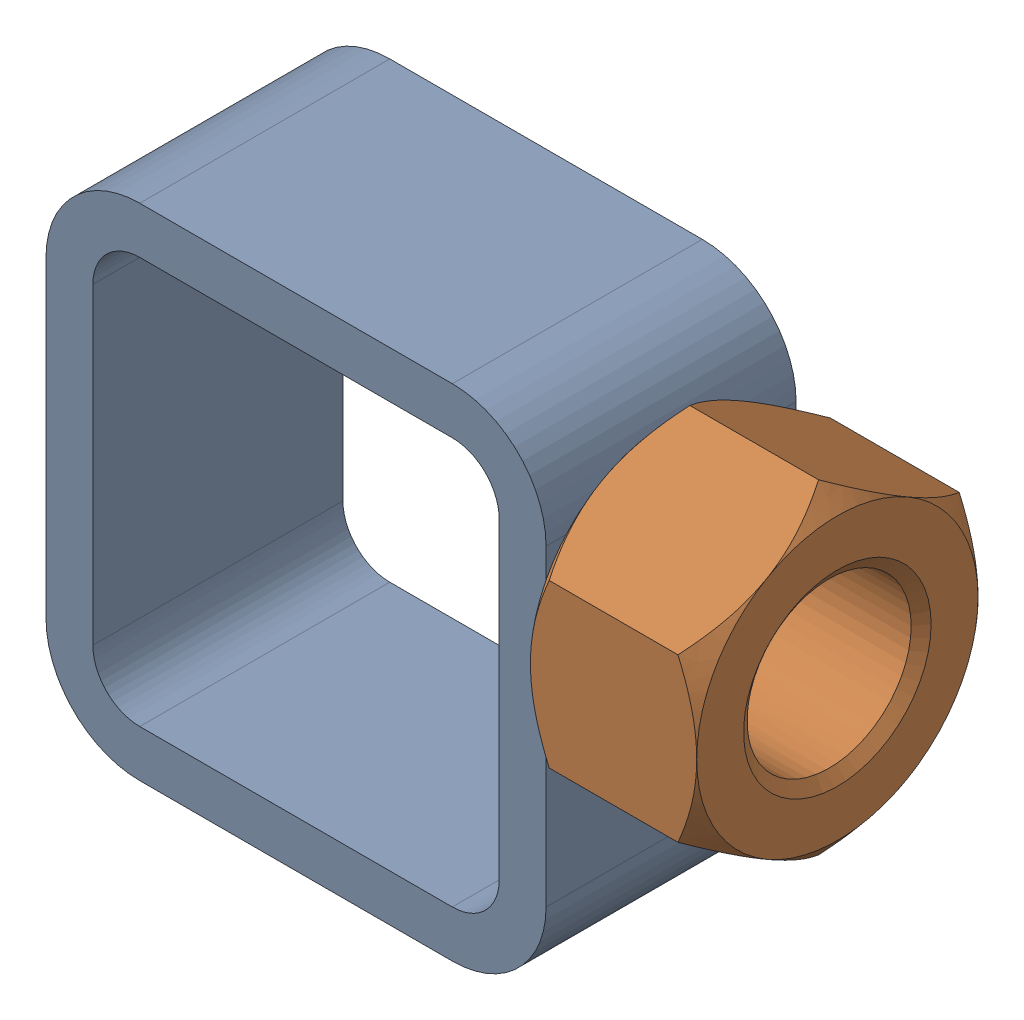
SolidWorks assembly 01-005-00-0-8, configuration Default. Lengths in mm.
Overall size (67.69 50.8 28.57).
2 component instances, 2 part files, 0 mates.
Components (placement in the parent):
- tube square_ai(PreviewCfg)-1: tube square_ai(PreviewCfg) [Default] at origin size (50.8 50.8 25.4)
- hex nut_ai(HNUT 0.7500-10-D-C)-1: hex nut_ai(HNUT 0.7500-10-D-C) [Default] at (67.691 31.75 0) x (0 0 -1) z (1 0 0) size (28.57 33 16.89)
